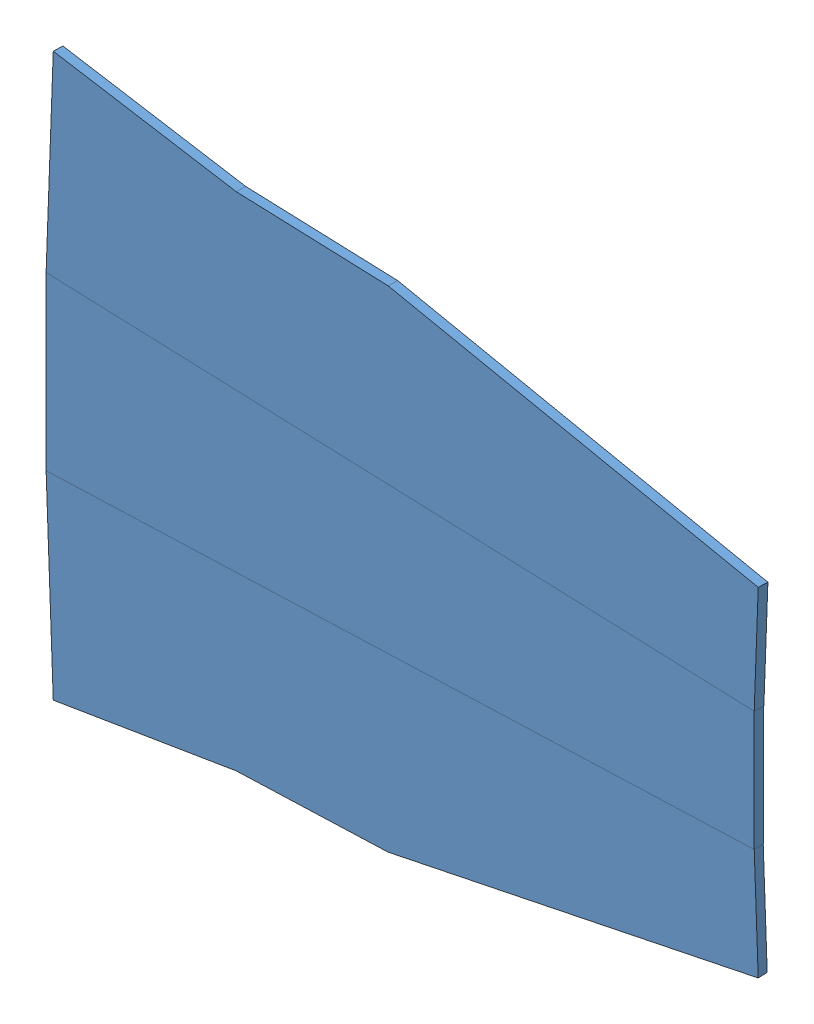
SolidWorks assembly batt_tray_unfold, configuration Default. Lengths in mm.
Overall size (329.91 258.99 28.22).
3 component instances, 1 part files, 9 mates.
Components (placement in the parent):
- batterytray-1: batterytray [bottom] at origin size (326.3 79.11 4.3)
- batterytray-2: batterytray [sde] at (5.2983 144.4313 65.4716) x (0.998656 -0.036635 0.036659) z (-0.036659 -0.999328 0) size (326.3 16.27 90)
- batterytray-3: batterytray [sde] at (5.1408 -144.437 140.2313) x (0.998656 0.036635 -0.036659) z (-0.036659 0.999328 0) size (326.3 16.27 90)
Mates (geometry in assembly coordinates):
- Coincident3: coincident aligned: plane of batterytray-1 through (0 0 0) normal (0 1 0)
- Coincident4: coincident aligned: plane of batterytray-1 through (0 0 0) normal (0 0 1)
- Coincident5: coincident aligned: plane of batterytray-1 through (0 0 0) normal (1 0 0)
- Coincident8: coincident: plane of batterytray-1 through (0 0 105) normal (0 0 1); plane of batterytray-2 through (326.3 27.585 105) normal (0 0 1)
- Coincident9: coincident: plane of batterytray-1 through (326.3 27.585 105) normal (0.036659 0.999328 0); plane of batterytray-2 through (1.4491 39.5018 65.4716) normal (-0.036659 -0.999328 0)
- Coincident12: coincident: point of batterytray-1; point of batterytray-2
- Coincident13: coincident: plane of batterytray-1 through (0 0 105) normal (0 0 1); plane of batterytray-3 through (5.1408 -144.437 105) normal (0 0 1)
- Coincident14: coincident: plane of batterytray-1 through (0 -39.555 105) normal (0.036659 -0.999328 0); plane of batterytray-3 through (1.2916 -39.5076 140.2313) normal (-0.036659 0.999328 0)
- Coincident15: coincident: point of batterytray-1; point of batterytray-3
